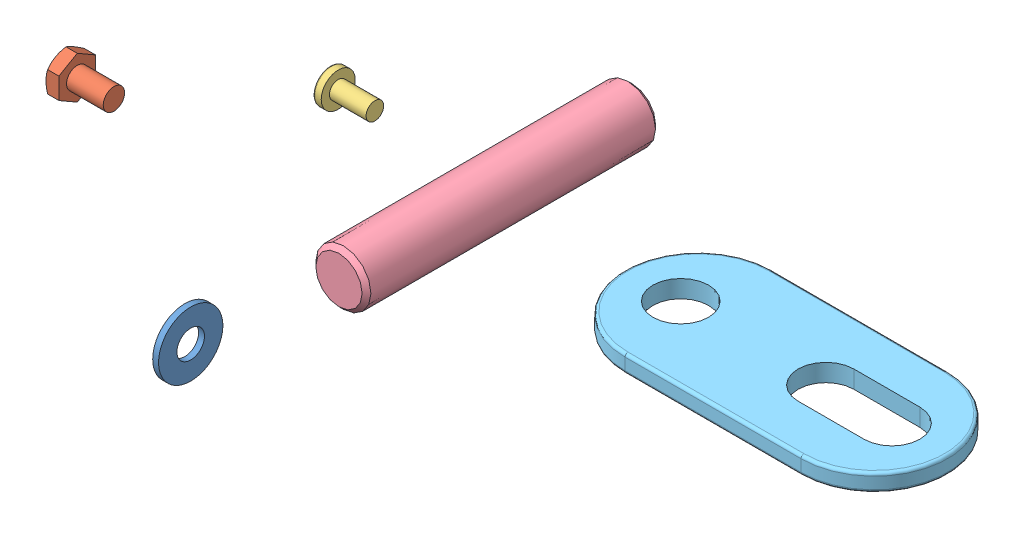
SolidWorks assembly Assem1, configuration Default. Lengths in mm.
Overall size (55.79 16.21 37.84).
5 component instances, 5 part files, 0 mates.
Components (placement in the parent):
- flat washer type a selected narrow_ai-1: flat washer type a selected narrow_ai [Selected Narrow FW 0.094] at (-47.6442 22.8342 10.8343) size (0.51 5.56 5.56)
- hex screw_ai-1: hex screw_ai [IN-HHMS 0.073-64x0.125x0.125-N] at (-66.5999 29.874 2.8185) size (4.29 3.67 3.17)
- pan cross head_ai-1: pan cross head_ai [CR-PHMS 0.06-80x0.125x0.125-N] at (-52.5156 31.7688 -5.6912) size (4.26 2.95 2.95)
- Axle-1: Axle [Default] at (-40.8061 28.0568 -7.8614) size (4.78 4.78 25.4)
- Flat-2: Flat [Default] at (-33.9268 17.7906 -17.8723) size (27.94 1.52 12.7)
